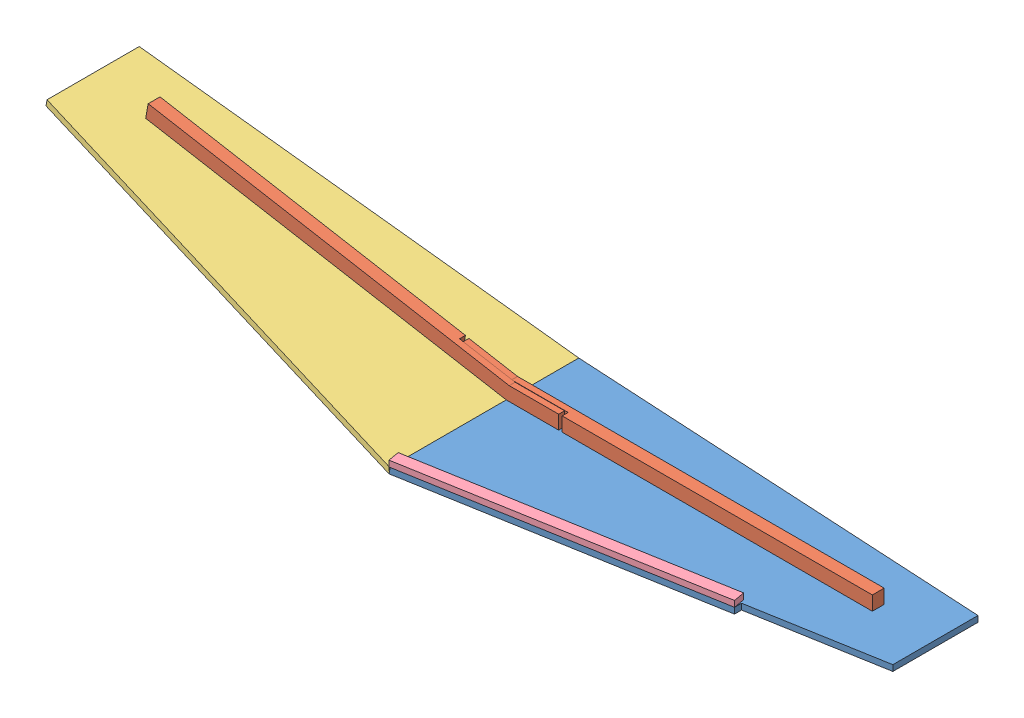
SolidWorks assembly BF109_Wing, configuration Default. Lengths in mm.
Overall size (755.05 90.58 170.24).
5 component instances, 4 part files, 7 mates.
Components (placement in the parent):
- BF109_RightWing-1: BF109_RightWing [Default] at origin size (380.42 5.33 170.24)
- BF109_Spar-1: BF109_Spar [Default] at origin size (375.56 25.75 10.67)
- BF109_LeftWing-1: BF109_LeftWing [Default] at (0.9262 5.253 0) x (-0.984808 0.173648 0) z (0 0 1) size (380.42 5.33 170.24)
- BF109_Spar-2: BF109_Spar [Default] at (0 0 119.8911) x (-0.984808 0.173648 0) z (0 0 -1) size (375.56 25.75 10.67)
- BF109_WingSpacer-1: BF109_WingSpacer [Default] at (0 5.334 0) x (1 0 0) z (0 1 0) size (266.31 56.08 5.33)
Mates (geometry in assembly coordinates):
- Coincident1: coincident anti-aligned: plane of BF109_LeftWing-1 through (-100.0566 17.6417 65.2795) normal (0 0 -1); plane of BF109_Spar-2 through (0 0 65.2795) normal (0 0 1)
- Coincident2: coincident aligned: plane of BF109_LeftWing-1 through (0 0 0) normal (-0.173648 -0.984808 0); plane of BF109_Spar-2 through (0 0 119.8911) normal (-0.173648 -0.984808 0)
- Coincident3: coincident anti-aligned: plane of BF109_LeftWing-1 through (-75.0425 13.231 65.2795) normal (-0.984808 0.173648 0); plane of BF109_Spar-2 through (-75.0424 13.232 119.8911) normal (0.984808 -0.173648 0)
- Parallel1: parallel aligned: line of BF109_RightWing-1 through (0 5.334 0) axis (0 0 1); line of BF109_LeftWing-1 through (0.9262 5.253 0) axis (0 0 1)
- Coincident9: coincident aligned: line of BF109_RightWing-1 through (0 0 0) axis (0 0 1); line of BF109_LeftWing-1 through (0 0 0) axis (0 0 1)
- Coincident10: coincident: point of BF109_RightWing-1; point of BF109_LeftWing-1
- Angle1: planar angle = 2.96706 rad anti-aligned: plane of BF109_LeftWing-1 through (0 0 0) normal (-0.173648 -0.984808 0); plane of BF109_RightWing-1 through (0 0 0) normal (0 -1 0)
